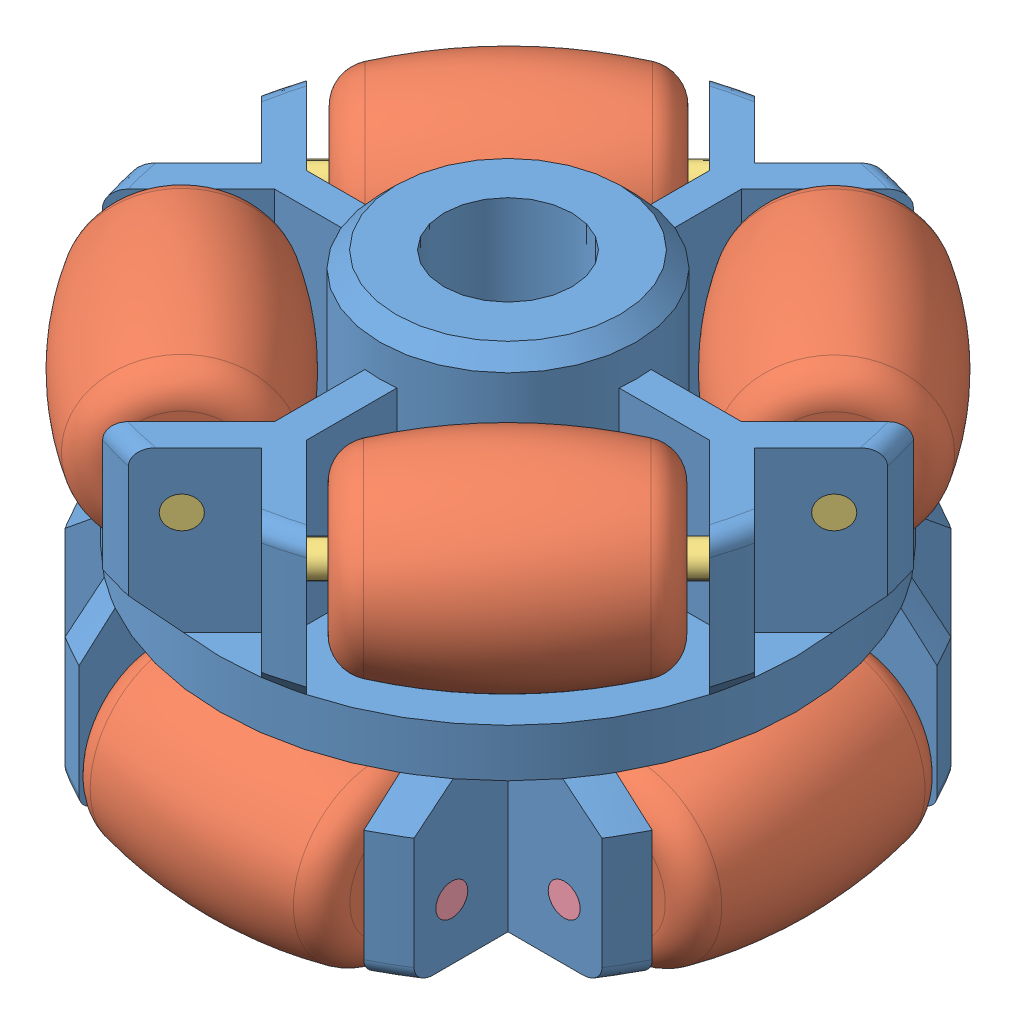
SolidWorks assembly Omniwheel, configuration Default. Lengths in mm.
Overall size (40.82 29 40.82).
17 component instances, 4 part files, 12 mates.
Components (placement in the parent):
- Frame-1: Frame [Default] at (-9.8083 0.9602 4.9461) size (39.31 29 39.31)
- SingleWheel-1: SingleWheel [Default] at (-19.9803 8.9602 -5.262) x (0.707107 0 -0.707107) z (0.707032 -0.014581 0.707032) size (15.85 12 12)
- AxisWheel^Omniwheel-1: AxisWheel^Omniwheel [Default] at (-17.5155 0.9602 12.6532) x (0.707107 0 0.707107) z (-0.707107 0 0.707107) size (2 2 21.8) (virtual)
- AxisWheel^Omniwheel-2: AxisWheel^Omniwheel [Default] at (-2.1012 0.9602 -2.761) x (-0.707107 0 -0.707107) z (0.707107 0 -0.707107) size (2 2 21.8) (virtual)
- AxisWheel^Omniwheel-3: AxisWheel^Omniwheel [Default] at (-17.5155 0.9602 -2.761) x (-0.707107 0 0.707107) z (-0.707107 0 -0.707107) size (2 2 21.8) (virtual)
- AxisWheel^Omniwheel-4: AxisWheel^Omniwheel [Default] at (-2.1012 0.9602 12.6532) x (0.707107 0 -0.707107) z (0.707107 0 0.707107) size (2 2 21.8) (virtual)
- SingleWheel-2: SingleWheel [Default] at (0.3636 8.9602 15.1541) x (-0.707107 0 0.707107) z (-0.707032 -0.014581 -0.707032) size (15.85 12 12)
- SingleWheel-3: SingleWheel [Default] at (0.3997 8.9602 -5.2259) x (0.707107 0 0.707107) z (-0.707032 -0.014581 0.707032) size (15.85 12 12)
- SingleWheel-4: SingleWheel [Default] at (-20.0164 8.9602 15.1181) x (-0.707107 0 -0.707107) z (0.707032 -0.014581 -0.707032) size (15.85 12 12)
- SingleWheel-5: SingleWheel [Default] at (-9.7828 -7.0398 -9.4648) size (15.85 12 12)
- AxisWheel2^Omniwheel-1: AxisWheel2^Omniwheel [Default] at (-20.7078 0.9602 4.9461) x (0 0 1) z (-1 0 0) size (2 2 21.8) (virtual)
- AxisWheel2^Omniwheel-2: AxisWheel2^Omniwheel [Default] at (-9.8083 0.9602 15.8456) size (2 2 21.8) (virtual)
- AxisWheel2^Omniwheel-3: AxisWheel2^Omniwheel [Default] at (1.0911 0.9602 4.9461) x (0 0 -1) z (1 0 0) size (2 2 21.8) (virtual)
- AxisWheel2^Omniwheel-4: AxisWheel2^Omniwheel [Default] at (-9.8083 0.9602 -5.9534) x (-1 0 0) z (0 0 -1) size (2 2 21.8) (virtual)
- SingleWheel-6: SingleWheel [Default] at (-24.2192 -7.0398 4.9206) x (0 0 -1) z (1 0 0) size (15.85 12 12)
- SingleWheel-7: SingleWheel [Default] at (-9.8339 -7.0398 19.357) x (-1 0 0) z (0 0 -1) size (15.85 12 12)
- SingleWheel-8: SingleWheel [Default] at (4.6025 -7.0398 4.9716) x (0 0 1) z (-1 0 0) size (15.85 12 12)
Mates (geometry in assembly coordinates):
- Concentrico1: concentric anti-aligned: cylinder of Frame-1 through (-27.7055 8.9602 2.4632) axis (-0.707107 0 0.707107) radius 1; cylinder of SingleWheel-1 through (-14.3765 8.9602 -10.8658) axis (0.707107 0 -0.707107) radius 1
- Distanza2: distance = 1 mm anti-aligned: plane of Frame-1 through (-23.3941 12.4602 3.9461) normal (0.707107 0 -0.707107); plane of SingleWheel-1 through (-25.5842 8.9602 0.3419) normal (-0.707107 0 0.707107)
- SulPosto1: in place: plane of Frame-1 through (-25.2226 12.4602 4.9461) normal (-0.707107 0 0.707107); plane of ? through (-15.0843 0 15.0843) normal (-0.707107 0 0.707107); moOrthogonalPlaneRef_w of Frame-1 through (-25.2226 12.4602 4.9461) normal (-0.707107 0 0.707107); unknown of ?; plane of Frame-1 through (-25.2226 12.4602 4.9461) normal (-0.707107 0 0.707107); plane of ? through (-15.0843 0 15.0843) normal (0.707107 0 0.707107); plane of Frame-1 through (-25.2226 12.4602 4.9461) normal (-0.707107 0 0.707107); unknown of AxisWheel^Omniwheel-1
- Coincidente3: coincident aligned: plane of Frame-1; plane of AxisWheel^Omniwheel-1
- Coincidente4: coincident aligned: moOrthogonalPlaneRef_w of Frame-1 through (-17.5155 0.9602 12.6532) normal (0 1 0); plane of AxisWheel^Omniwheel-1
- Coincidente5: coincident anti-aligned: moOrthogonalPlaneRef_w of Frame-1 through (-17.5155 0.9602 12.6532) normal (-0.707107 0 -0.707107); plane of AxisWheel^Omniwheel-1 through (-17.5155 0.9602 12.6532) normal (0.707107 0 0.707107)
- Concentrico2: concentric anti-aligned: cylinder of Frame-1 through (-20.7078 -7.0398 -9.4648) axis (-1 0 0) radius 1; cylinder of SingleWheel-5 through (-1.8578 -7.0398 -9.4648) axis (1 0 0) radius 1
- Distanza3: distance = 1 mm anti-aligned: plane of SingleWheel-5 through (-17.7078 -7.0398 -9.4648) normal (-1 0 0); plane of Frame-1 through (-18.7078 -10.5398 -5.3676) normal (1 0 0)
- SulPosto3: in place: plane of Frame-1 through (-20.7078 -10.5398 -5.9534) normal (-1 0 0); plane of ? through (-20.7078 0 0) normal (-1 0 0); plane of Frame-1 through (-20.7078 -10.5398 -5.9534) normal (-1 0 0); line of ? through (-55 -20.7078 0) axis (0 0 1); plane of Frame-1 through (-20.7078 -10.5398 -5.9534) normal (-1 0 0); plane of ? through (-20.7078 0 0) normal (0 0 1); plane of Frame-1 through (-20.7078 -10.5398 -5.9534) normal (-1 0 0); unknown of AxisWheel2^Omniwheel-1
- Coincidente9: coincident aligned: plane of Frame-1; plane of AxisWheel2^Omniwheel-1
- Coincidente10: coincident aligned: moOrthogonalPlaneRef_w of Frame-1 through (-20.7078 0.9602 4.9461) normal (0 1 0); plane of AxisWheel2^Omniwheel-1
- Coincidente11: coincident anti-aligned: moOrthogonalPlaneRef_w of Frame-1 through (-20.7078 0.9602 4.9461) normal (0 0 -1); plane of AxisWheel2^Omniwheel-1 through (-20.7078 0.9602 4.9461) normal (0 0 1)
